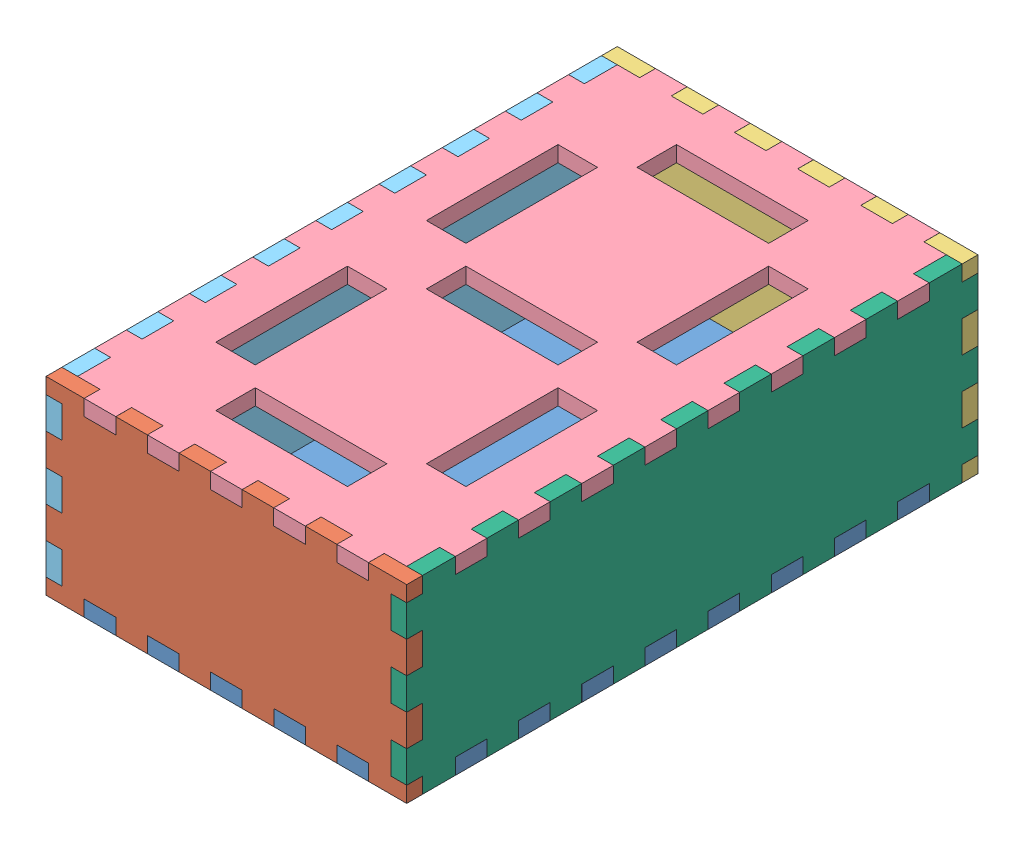
SolidWorks assembly Assem1, configuration Default. Lengths in mm.
Overall size (137.01 72 217).
6 component instances, 6 part files, 14 mates.
Components (placement in the parent):
- BOTTOM_PLANE-1: BOTTOM_PLANE [Default] at (-38.3848 2.859 16.2746) size (137 6 217)
- Part1-1: Part1 [Default] at (-38.3848 2.859 118.7746) size (137 72 6)
- BACK_PLANE-1: BACK_PLANE [Default] at (-38.3848 2.859 -92.2254) size (137 72 6)
- TOP_PLANE-1: TOP_PLANE [Default] at (-38.3996 68.859 16.2746) size (137 6 217)
- RIGHT_SIDE_PLANE-1: RIGHT_SIDE_PLANE [Default] at (-96.8633 68.859 16.2746) x (0 0 1) z (-1 0 0) size (217 72 6)
- LEFT_SIDE_PLANE-1: LEFT_SIDE_PLANE [Default] at (30.1004 68.859 16.2746) x (0 0 1) z (-1 0 0) size (217 72 6)
Mates (geometry in assembly coordinates):
- Coincident5: coincident anti-aligned: plane of BOTTOM_PLANE-1 through (15.6152 2.859 -86.2254) normal (1 0 0); plane of BACK_PLANE-1 through (15.6152 2.859 -86.2254) normal (-1 0 0)
- Coincident9: coincident anti-aligned: plane of BOTTOM_PLANE-1 through (-38.3848 8.859 16.2746) normal (0 1 0); plane of BACK_PLANE-1 through (-38.3848 8.859 -86.2254) normal (0 -1 0)
- Coincident10: coincident anti-aligned: plane of BOTTOM_PLANE-1 through (-100.8848 8.859 -86.2254) normal (0 0 -1); plane of BACK_PLANE-1 through (-38.3848 2.859 -86.2254) normal (0 0 1)
- Parallel4: parallel anti-aligned: plane of BACK_PLANE-1 through (-80.3848 2.859 -86.2254) normal (-1 0 0); plane of TOP_PLANE-1 through (-80.3996 68.859 16.2746) normal (1 0 0)
- Coincident15: coincident anti-aligned: plane of Part1-1 through (-38.3848 68.859 124.7746) normal (0 1 0); plane of TOP_PLANE-1 through (-38.3996 68.859 16.2746) normal (0 -1 0)
- Coincident16: coincident anti-aligned: plane of Part1-1 through (-38.3848 2.859 118.7746) normal (0 0 -1); plane of TOP_PLANE-1 through (-100.8996 74.859 118.7746) normal (0 0 1)
- Coincident21: coincident anti-aligned: plane of BOTTOM_PLANE-1 through (-38.3848 2.859 106.2746) normal (0 0 1); plane of LEFT_SIDE_PLANE-1 through (24.1004 8.8596 106.2746) normal (0 0 -1)
- Coincident22: coincident anti-aligned: plane of TOP_PLANE-1 through (-38.3996 68.859 106.2746) normal (0 0 1); plane of LEFT_SIDE_PLANE-1 through (24.1004 68.859 106.2746) normal (0 0 -1)
- Coincident23: coincident anti-aligned: plane of TOP_PLANE-1 through (24.1004 74.859 118.7746) normal (1 0 0); plane of LEFT_SIDE_PLANE-1 through (24.1004 68.859 16.2746) normal (-1 0 0)
- Coincident26: coincident anti-aligned: plane of BOTTOM_PLANE-1 through (-38.3848 8.859 16.2746) normal (0 1 0); plane of Part1-1 through (-38.3848 8.859 124.7746) normal (0 -1 0)
- Coincident27: coincident anti-aligned: plane of BOTTOM_PLANE-1 through (-80.3848 2.859 124.7746) normal (1 0 0); plane of Part1-1 through (-80.3848 2.859 124.7746) normal (-1 0 0)
- Coincident28: coincident anti-aligned: plane of Part1-1 through (24.1152 56.859 118.7746) normal (0 1 0); plane of LEFT_SIDE_PLANE-1 through (30.1004 56.859 124.7746) normal (0 -1 0)
- Coincident29: coincident anti-aligned: plane of Part1-1 through (-38.3848 2.859 118.7746) normal (0 0 -1); plane of RIGHT_SIDE_PLANE-1 through (-106.8996 68.859 118.7746) normal (0 0 1)
- Coincident30: coincident anti-aligned: plane of BACK_PLANE-1 through (-38.3848 8.859 -92.2254) normal (0 1 0); plane of RIGHT_SIDE_PLANE-1 through (-100.8996 8.859 -86.2254) normal (0 -1 0)
